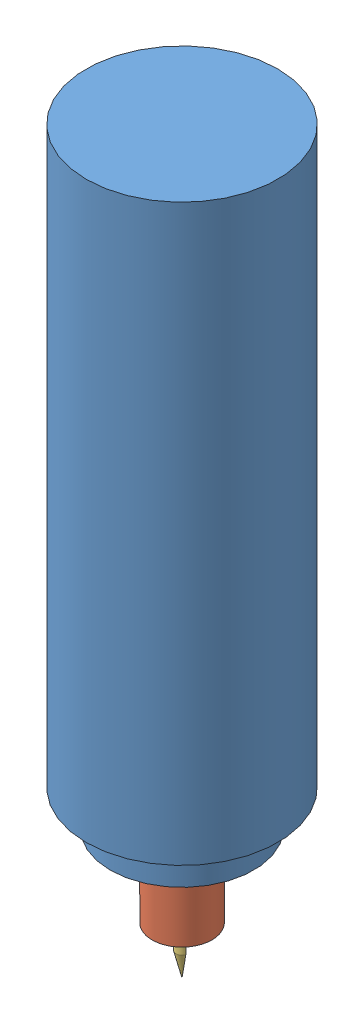
SolidWorks assembly spindle, configuration Default. Lengths in mm.
Overall size (80 309 80).
3 component instances, 3 part files, 3 mates.
Components (placement in the parent):
- spindle body-1: spindle body [Default] at (87.2179 34.7039 190.3379) size (80 255 80)
- spindle rotor-1: spindle rotor [Default] at (87.2179 -14.2961 190.3379) x (0.42662 0 0.904431) z (-0.904431 0 0.42662) size (25 44 25)
- dumb bit-1: dumb bit [Default] at (87.606 -19.2961 189.1497) x (0 -1 0) z (0.950566 0 0.310524) size (30 5 5)
Mates (geometry in assembly coordinates):
- Coincident3: coincident anti-aligned: circle of spindle body-1; circle of spindle rotor-1
- Concentric2: concentric anti-aligned: cylinder of spindle rotor-1 through (87.2179 -4.2961 190.3379) axis (0 -1 0) radius 5; cylinder of dumb bit-1 through (87.2179 -4.2961 190.3379) axis (0 1 0) radius 2.5
- Coincident5: coincident anti-aligned: plane of spindle rotor-1 through (87.2179 -4.2961 190.3379) normal (0 -1 0); plane of dumb bit-1 through (87.9942 -4.2961 187.9615) normal (0 1 0)
